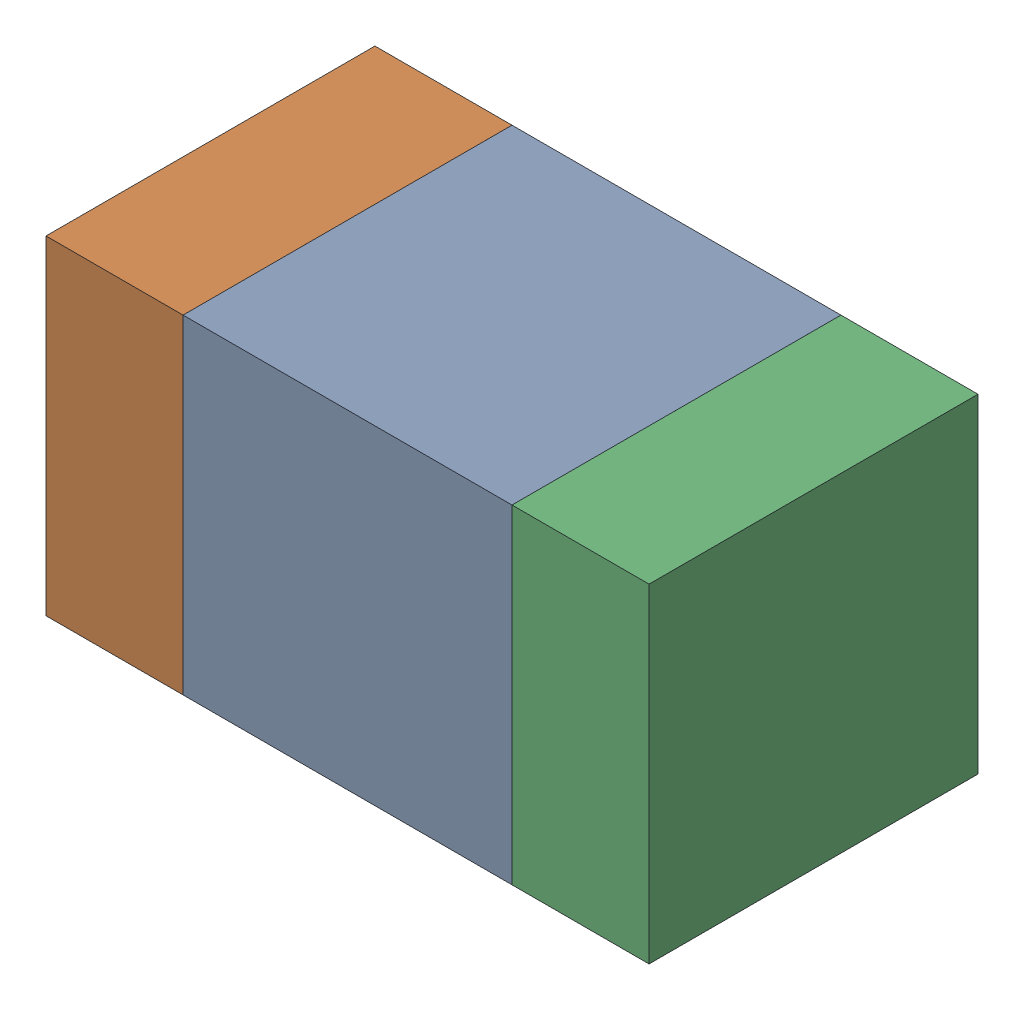
SolidWorks assembly C322_1PCB, configuration Default. Lengths in mm.
Overall size (1.1 0.6 0.6).
6 component instances, 2 part files, 0 mates.
Components (placement in the parent):
- 761606048-1: 761606048 [Default] at (136.5343 121.55 -2.2638) size (0.6 0.6 0.6)
  - Extruded_9-1: Extruded_9 [Default] at origin size (0.6 0.6 0.6)
- 854785160-1: 854785160 [Default] at (136.1093 121.55 -2.2638) size (0.25 0.6 0.6)
  - Extruded_19-1: Extruded_19 [Default] at origin size (0.25 0.6 0.6)
- 854785160-2: 854785160 [Default] at (136.9593 121.55 -2.2638) size (0.25 0.6 0.6)
  - Extruded_19-1: Extruded_19 [Default] at origin size (0.25 0.6 0.6)
